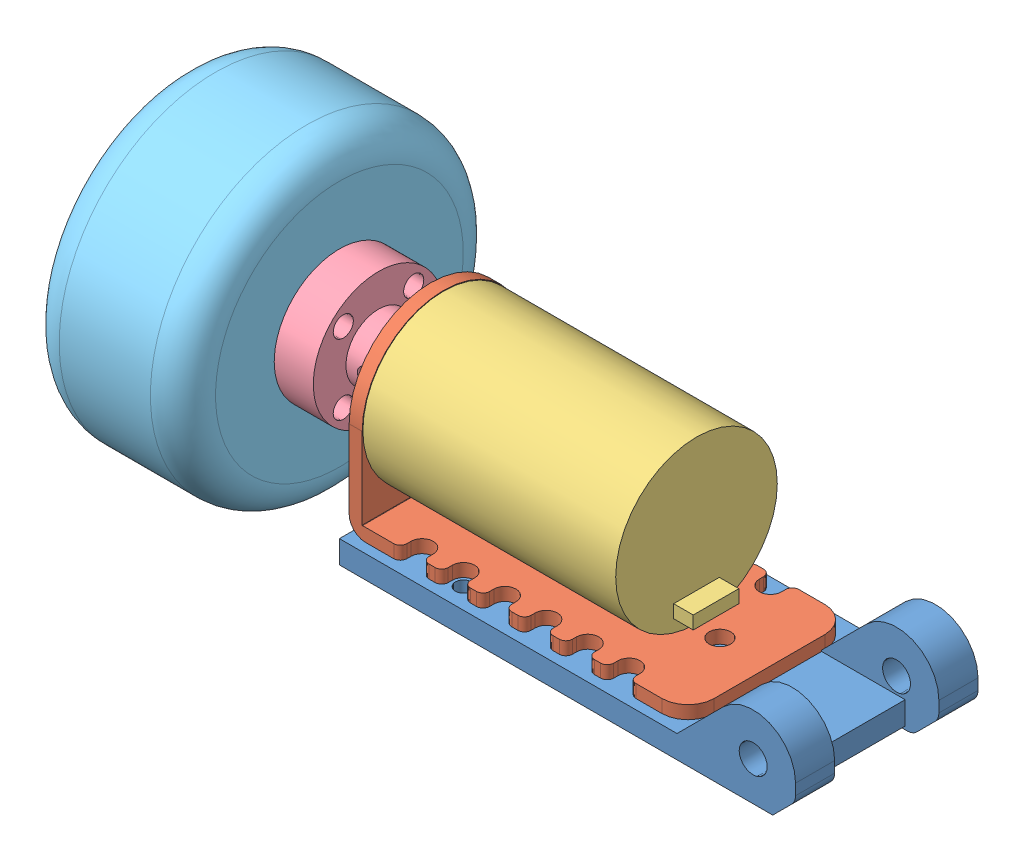
SolidWorks assembly Motor Assembly, configuration Standard. Lengths in mm.
Overall size (108 48 48).
5 component instances, 5 part files, 10 mates.
Components (placement in the parent):
- Motor Mount-1: Motor Mount [Standard] at origin size (70 13 28)
- Motor Mount Plate-1: Motor Mount Plate [Standard] at (-33 4 12.5) size (52 27 25)
- Motor-1: Motor [Standard] at (5.8 18.5 0) x (0 0 1) z (-1 0 0) size (24.8 24.8 53.8)
- WheelHub2-1: WheelHub2 [Standard] at (-49 18.5 0) x (0 -1 0) z (0 0 1) size (20 12 20)
- Wheel-1: Wheel [Standard] at (-73 18.5 0) x (0 0 -1) z (1 0 0) size (48 48 24)
Mates (geometry in assembly coordinates):
- Deckungsgleich1: coincident anti-aligned: plane of Motor Mount-1 through (0 4 0) normal (0 1 0); plane of Motor Mount Plate-1 through (-33 4 -12.5) normal (0 -1 0)
- Abstand1: distance = 1.5 mm: line of Motor Mount Plate-1 through (-32.5 4 -12.5) axis (1 0 0); line of Motor Mount-1 through (16.8076 4 -14) axis (-1 0 0)
- Deckungsgleich5: coincident aligned: plane of Motor Mount-1 through (-35 4 -14) normal (-1 0 0); plane of Motor Mount Plate-1 through (-35 31 -12.5) normal (-1 0 0)
- Deckungsgleich7: coincident anti-aligned: circle of Motor Mount Plate-1; circle of Motor-1
- Konzentrisch2: concentric anti-aligned: circle of Motor-1; circle of ?
- Abstand2: distance = 1 mm anti-aligned: plane of Motor Mount Plate-1 through (-35 31 -12.5) normal (-1 0 0); plane of ? through (-36 18.5 0) normal (1 0 0)
- Konzentrisch3: concentric anti-aligned: circle of Motor-1; circle of WheelHub2-1
- Abstand3: distance = 2 mm anti-aligned: plane of WheelHub2-1 through (-37 18.5 0) normal (1 0 0); plane of Motor Mount Plate-1 through (-35 31 -12.5) normal (-1 0 0)
- Konzentrisch4: concentric: circle of WheelHub2-1; circle of Wheel-1
- Deckungsgleich8: coincident anti-aligned: plane of WheelHub2-1 through (-49 18.5 0) normal (-1 0 0); plane of Wheel-1 through (-49 18.5 0) normal (1 0 0)
